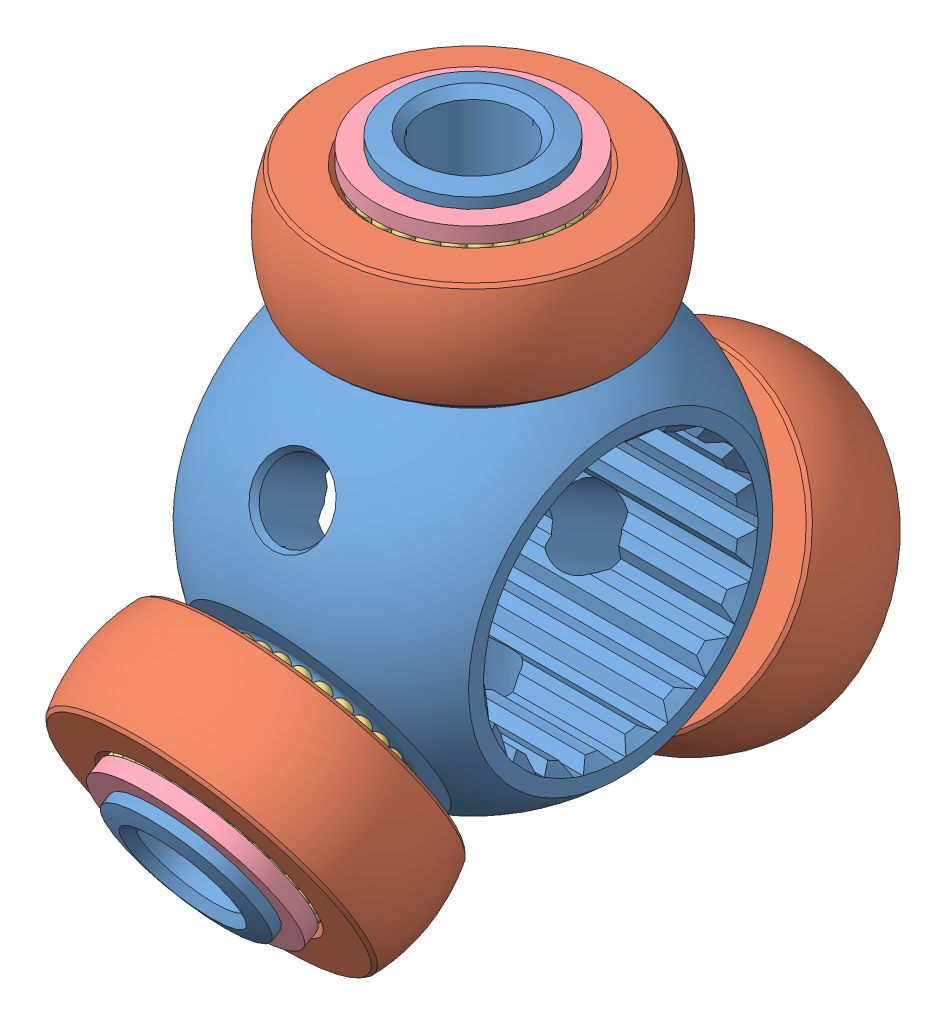
SolidWorks assembly RCV D4672-TA, configuration Default. Lengths in mm.
Overall size (25.48 60.73 70.13).
94 component instances, 4 part files, 0 mates.
Components (placement in the parent):
- FSAE Tripod V2-1: FSAE Tripod V2 [Default] at (-43.6945 4.946 19.6967) size (24 46.2 52.92)
- FSAE roller_2451-1: FSAE roller_2451 [Default] at (-43.6945 -7.4365 -1.7504) x (0 0.5 0.866025) z (-1 0 0) size (25.48 25.48 25.48)
- FSAE roller_2451-2: FSAE roller_2451 [Default] at (-43.6945 -7.4365 41.1438) x (0 0.5 -0.866025) z (1 0 0) size (25.48 25.48 25.48)
- FSAE roller_2451-3: FSAE roller_2451 [Default] at (-43.6945 29.711 19.6967) x (0 -1 0) z (-1 0 0) size (25.48 25.48 25.48)
- needle-1: needle [Default] at (-42.3538 -7.5483 -1.6859) x (1 0 0) z (0 0.5 0.866025) size (1.51 1.51 10.16)
- needle-2: needle [Default] at (-42.3574 -7.2961 -1.8314) x (0.976635 0.186114 -0.107453) z (0 0.5 0.866025) size (1.51 1.51 10.16)
- needle-3: needle [Default] at (-42.4235 -7.0506 -1.9732) x (0.907631 0.363531 -0.209884) z (0 0.5 0.866025) size (1.51 1.51 10.16)
- needle-4: needle [Default] at (-42.5489 -6.823 -2.1046) x (0.796213 0.523959 -0.302508) z (0 0.5 0.866025) size (1.51 1.51 10.16)
- needle-5: needle [Default] at (-42.7279 -6.6242 -2.2194) x (0.647588 0.659903 -0.380995) z (0 0.5 0.866025) size (1.51 1.51 10.16)
- needle-6: needle [Default] at (-42.9521 -6.4632 -2.3123) x (0.468701 0.76501 -0.441678) z (0 0.5 0.866025) size (1.51 1.51 10.16)
- needle-7: needle [Default] at (-43.2109 -6.3478 -2.3789) x (0.267911 0.834367 -0.481722) z (0 0.5 0.866025) size (1.51 1.51 10.16)
- needle-8: needle [Default] at (-43.4924 -6.2833 -2.4162) x (0.054602 0.864733 -0.499254) z (0 0.5 0.866025) size (1.51 1.51 10.16)
- needle-9: needle [Default] at (-43.7833 -6.2726 -2.4224) x (-0.161259 0.854691 -0.493456) z (0 0.5 0.866025) size (1.51 1.51 10.16)
- needle-10: needle [Default] at (-44.07 -6.3163 -2.3971) x (-0.369585 0.804708 -0.464599) z (0 0.5 0.866025) size (1.51 1.51 10.16)
- needle-11: needle [Default] at (-44.3392 -6.4124 -2.3417) x (-0.560639 0.717121 -0.41403) z (0 0.5 0.866025) size (1.51 1.51 10.16)
- needle-12: needle [Default] at (-44.5783 -6.5563 -2.2586) x (-0.725495 0.596023 -0.344114) z (0 0.5 0.866025) size (1.51 1.51 10.16)
- needle-13: needle [Default] at (-44.7761 -6.7413 -2.1517) x (-0.856447 0.447072 -0.258117) z (0 0.5 0.866025) size (1.51 1.51 10.16)
- needle-14: needle [Default] at (-44.9233 -6.9589 -2.0261) x (-0.947378 0.277229 -0.160058) z (0 0.5 0.866025) size (1.51 1.51 10.16)
- needle-15: needle [Default] at (-45.0131 -7.1987 -1.8877) x (-0.994037 0.094432 -0.05452) z (0 0.5 0.866025) size (1.51 1.51 10.16)
- needle-16: needle [Default] at (-45.0413 -7.4497 -1.7428) x (-0.994245 -0.092779 0.053566) z (0 0.5 0.866025) size (1.51 1.51 10.16)
- needle-17: needle [Default] at (-45.0065 -7.7 -1.5982) x (-0.947991 -0.275654 0.159149) z (0 0.5 0.866025) size (1.51 1.51 10.16)
- needle-18: needle [Default] at (-44.9105 -7.9381 -1.4608) x (-0.857437 -0.445647 0.257295) z (0 0.5 0.866025) size (1.51 1.51 10.16)
- needle-19: needle [Default] at (-44.7576 -8.1527 -1.3369) x (-0.726814 -0.594816 0.343417) z (0 0.5 0.866025) size (1.51 1.51 10.16)
- needle-20: needle [Default] at (-44.555 -8.3338 -1.2323) x (-0.562228 -0.716188 0.413491) z (0 0.5 0.866025) size (1.51 1.51 10.16)
- needle-21: needle [Default] at (-44.3122 -8.473 -1.152) x (-0.371368 -0.804092 0.464243) z (0 0.5 0.866025) size (1.51 1.51 10.16)
- needle-22: needle [Default] at (-44.0406 -8.5637 -1.0996) x (-0.163154 -0.854421 0.4933) z (0 0.5 0.866025) size (1.51 1.51 10.16)
- needle-23: needle [Default] at (-43.7528 -8.6018 -1.0776) x (0.052685 -0.864823 0.499306) z (0 0.5 0.866025) size (1.51 1.51 10.16)
- needle-24: needle [Default] at (-43.4622 -8.5854 -1.0871) x (0.266061 -0.834811 0.481978) z (0 0.5 0.866025) size (1.51 1.51 10.16)
- needle-25: needle [Default] at (-43.1825 -8.5153 -1.1275) x (0.467004 -0.765787 0.442128) z (0 0.5 0.866025) size (1.51 1.51 10.16)
- needle-26: needle [Default] at (-42.9268 -8.3949 -1.1971) x (0.646124 -0.660979 0.381616) z (0 0.5 0.866025) size (1.51 1.51 10.16)
- needle-27: needle [Default] at (-42.7069 -8.2296 -1.2925) x (0.79505 -0.525282 0.303272) z (0 0.5 0.866025) size (1.51 1.51 10.16)
- needle-28: needle [Default] at (-42.5332 -8.0272 -1.4093) x (0.906823 -0.365039 0.210755) z (0 0.5 0.866025) size (1.51 1.51 10.16)
- needle-29: needle [Default] at (-42.4137 -7.7973 -1.5421) x (0.97622 -0.187737 0.10839) z (0 0.5 0.866025) size (1.51 1.51 10.16)
- needle-30: needle [Default] at (-42.3538 29.711 19.5676) x (1 0 0) z (0 -1 0) size (1.51 1.51 10.16)
- needle-31: needle [Default] at (-42.3538 -7.3247 41.2084) x (1 0 0) z (0 0.5 -0.866025) size (1.51 1.51 10.16)
- needle-32: needle [Default] at (-42.4137 29.711 19.2801) x (0.97622 0 -0.21678) z (0 -1 0) size (1.51 1.51 10.16)
- needle-33: needle [Default] at (-42.4137 -7.0756 41.3522) x (0.97622 0.187737 0.10839) z (0 0.5 -0.866025) size (1.51 1.51 10.16)
- needle-34: needle [Default] at (-42.5332 29.711 19.0146) x (0.906823 0 -0.421511) z (0 -1 0) size (1.51 1.51 10.16)
- needle-35: needle [Default] at (-42.5332 -6.8457 41.4849) x (0.906823 0.365039 0.210755) z (0 0.5 -0.866025) size (1.51 1.51 10.16)
- needle-36: needle [Default] at (-42.7069 29.711 18.7809) x (0.79505 0 -0.606544) z (0 -1 0) size (1.51 1.51 10.16)
- needle-37: needle [Default] at (-42.7069 -6.6434 41.6017) x (0.79505 0.525282 0.303272) z (0 0.5 -0.866025) size (1.51 1.51 10.16)
- needle-38: needle [Default] at (-42.9268 29.711 18.5901) x (0.646124 0 -0.763232) z (0 -1 0) size (1.51 1.51 10.16)
- needle-39: needle [Default] at (-42.9268 -6.4781 41.6972) x (0.646124 0.660979 0.381616) z (0 0.5 -0.866025) size (1.51 1.51 10.16)
- needle-40: needle [Default] at (-43.1825 29.711 18.4509) x (0.467004 0 -0.884255) z (0 -1 0) size (1.51 1.51 10.16)
- needle-41: needle [Default] at (-43.1825 -6.3576 41.7667) x (0.467004 0.765787 0.442128) z (0 0.5 -0.866025) size (1.51 1.51 10.16)
- needle-42: needle [Default] at (-43.4622 29.711 18.37) x (0.266061 0 -0.963956) z (0 -1 0) size (1.51 1.51 10.16)
- needle-43: needle [Default] at (-43.4622 -6.2875 41.8072) x (0.266061 0.834811 0.481978) z (0 0.5 -0.866025) size (1.51 1.51 10.16)
- needle-44: needle [Default] at (-43.7528 29.711 18.3511) x (0.052685 0 -0.998611) z (0 -1 0) size (1.51 1.51 10.16)
- needle-45: needle [Default] at (-43.7528 -6.2711 41.8166) x (0.052685 0.864823 0.499306) z (0 0.5 -0.866025) size (1.51 1.51 10.16)
- needle-46: needle [Default] at (-44.0406 29.711 18.3951) x (-0.163154 0 -0.986601) z (0 -1 0) size (1.51 1.51 10.16)
- needle-47: needle [Default] at (-44.0406 -6.3092 41.7947) x (-0.163154 0.854421 0.4933) z (0 0.5 -0.866025) size (1.51 1.51 10.16)
- needle-48: needle [Default] at (-44.3122 29.711 18.4999) x (-0.371368 0 -0.928486) z (0 -1 0) size (1.51 1.51 10.16)
- needle-49: needle [Default] at (-44.3122 -6.4 41.7423) x (-0.371368 0.804092 0.464243) z (0 0.5 -0.866025) size (1.51 1.51 10.16)
- needle-50: needle [Default] at (-44.555 29.711 18.6606) x (-0.562228 0 -0.826982) z (0 -1 0) size (1.51 1.51 10.16)
- needle-51: needle [Default] at (-44.555 -6.5392 41.6619) x (-0.562228 0.716188 0.413491) z (0 0.5 -0.866025) size (1.51 1.51 10.16)
- needle-52: needle [Default] at (-44.7576 29.711 18.8697) x (-0.726814 0 -0.686834) z (0 -1 0) size (1.51 1.51 10.16)
- needle-53: needle [Default] at (-44.7576 -6.7203 41.5573) x (-0.726814 0.594816 0.343417) z (0 0.5 -0.866025) size (1.51 1.51 10.16)
- needle-54: needle [Default] at (-44.9105 29.711 19.1175) x (-0.857437 0 -0.514589) z (0 -1 0) size (1.51 1.51 10.16)
- needle-55: needle [Default] at (-44.9105 -6.9349 41.4334) x (-0.857437 0.445647 0.257295) z (0 0.5 -0.866025) size (1.51 1.51 10.16)
- needle-56: needle [Default] at (-45.0065 29.711 19.3924) x (-0.947991 0 -0.318298) z (0 -1 0) size (1.51 1.51 10.16)
- needle-57: needle [Default] at (-45.0065 -7.1729 41.296) x (-0.947991 0.275654 0.159149) z (0 0.5 -0.866025) size (1.51 1.51 10.16)
- needle-58: needle [Default] at (-45.0413 29.711 19.6814) x (-0.994245 0 -0.107132) z (0 -1 0) size (1.51 1.51 10.16)
- needle-59: needle [Default] at (-45.0413 -7.4232 41.1515) x (-0.994245 0.092779 0.053566) z (0 0.5 -0.866025) size (1.51 1.51 10.16)
- needle-60: needle [Default] at (-45.0131 29.711 19.9712) x (-0.994037 0 0.10904) z (0 -1 0) size (1.51 1.51 10.16)
- needle-61: needle [Default] at (-45.0131 -7.6742 41.0066) x (-0.994037 -0.094432 -0.05452) z (0 0.5 -0.866025) size (1.51 1.51 10.16)
- needle-62: needle [Default] at (-44.9233 29.711 20.2482) x (-0.947378 0 0.320117) z (0 -1 0) size (1.51 1.51 10.16)
- needle-63: needle [Default] at (-44.9233 -7.914 40.8681) x (-0.947378 -0.277229 -0.160058) z (0 0.5 -0.866025) size (1.51 1.51 10.16)
- needle-64: needle [Default] at (-44.7761 29.711 20.4994) x (-0.856447 0 0.516234) z (0 -1 0) size (1.51 1.51 10.16)
- needle-65: needle [Default] at (-44.7761 -8.1316 40.7425) x (-0.856447 -0.447072 -0.258117) z (0 0.5 -0.866025) size (1.51 1.51 10.16)
- needle-66: needle [Default] at (-44.5783 29.711 20.7131) x (-0.725495 0 0.688228) z (0 -1 0) size (1.51 1.51 10.16)
- needle-67: needle [Default] at (-44.5783 -8.3166 40.6357) x (-0.725495 -0.596023 -0.344114) z (0 0.5 -0.866025) size (1.51 1.51 10.16)
- needle-68: needle [Default] at (-44.3392 29.711 20.8792) x (-0.560639 0 0.82806) z (0 -1 0) size (1.51 1.51 10.16)
- needle-69: needle [Default] at (-44.3392 -8.4606 40.5526) x (-0.560639 -0.717121 -0.41403) z (0 0.5 -0.866025) size (1.51 1.51 10.16)
- needle-70: needle [Default] at (-44.07 29.711 20.9902) x (-0.369585 0 0.929197) z (0 -1 0) size (1.51 1.51 10.16)
- needle-71: needle [Default] at (-44.07 -8.5566 40.4971) x (-0.369585 -0.804708 -0.464599) z (0 0.5 -0.866025) size (1.51 1.51 10.16)
- needle-72: needle [Default] at (-43.7833 29.711 21.0407) x (-0.161259 0 0.986912) z (0 -1 0) size (1.51 1.51 10.16)
- needle-73: needle [Default] at (-43.7833 -8.6003 40.4719) x (-0.161259 -0.854691 -0.493456) z (0 0.5 -0.866025) size (1.51 1.51 10.16)
- needle-74: needle [Default] at (-43.4924 29.711 21.0283) x (0.054602 0 0.998508) z (0 -1 0) size (1.51 1.51 10.16)
- needle-75: needle [Default] at (-43.4924 -8.5897 40.478) x (0.054602 -0.864733 -0.499254) z (0 0.5 -0.866025) size (1.51 1.51 10.16)
- needle-76: needle [Default] at (-43.2109 29.711 20.9538) x (0.267911 0 0.963444) z (0 -1 0) size (1.51 1.51 10.16)
- needle-77: needle [Default] at (-43.2109 -8.5251 40.5153) x (0.267911 -0.834367 -0.481722) z (0 0.5 -0.866025) size (1.51 1.51 10.16)
- needle-78: needle [Default] at (-42.9521 29.711 20.8205) x (0.468701 0 0.883357) z (0 -1 0) size (1.51 1.51 10.16)
- needle-79: needle [Default] at (-42.9521 -8.4097 40.582) x (0.468701 -0.76501 -0.441678) z (0 0.5 -0.866025) size (1.51 1.51 10.16)
- needle-80: needle [Default] at (-42.7279 29.711 20.6347) x (0.647588 0 0.761991) z (0 -1 0) size (1.51 1.51 10.16)
- needle-81: needle [Default] at (-42.7279 -8.2488 40.6749) x (0.647588 -0.659903 -0.380995) z (0 0.5 -0.866025) size (1.51 1.51 10.16)
- needle-82: needle [Default] at (-42.5489 29.711 20.4051) x (0.796213 0 0.605016) z (0 -1 0) size (1.51 1.51 10.16)
- needle-83: needle [Default] at (-42.5489 -8.0499 40.7897) x (0.796213 -0.523959 -0.302508) z (0 0.5 -0.866025) size (1.51 1.51 10.16)
- needle-84: needle [Default] at (-42.4235 29.711 20.1423) x (0.907631 0 0.419769) z (0 -1 0) size (1.51 1.51 10.16)
- needle-85: needle [Default] at (-42.4235 -7.8224 40.921) x (0.907631 -0.363531 -0.209884) z (0 0.5 -0.866025) size (1.51 1.51 10.16)
- needle-86: needle [Default] at (-42.3574 29.711 19.8588) x (0.976635 0 0.214906) z (0 -1 0) size (1.51 1.51 10.16)
- needle-87: needle [Default] at (-42.3574 -7.5768 41.0628) x (0.976635 -0.186114 -0.107453) z (0 0.5 -0.866025) size (1.51 1.51 10.16)
- Tripod Retainer-1: Tripod Retainer [Default] at (-43.6945 -8.0715 -2.8502) x (0.973299 0.198788 -0.11477) z (0 0.5 0.866025) size (15.88 15.88 1.27)
- Tripod Retainer-2: Tripod Retainer [Default] at (-43.6945 -8.0715 42.2437) x (0.973299 -0.198788 -0.11477) z (0 0.5 -0.866025) size (15.88 15.88 1.27)
- Tripod Retainer-3: Tripod Retainer [Default] at (-43.6945 30.981 19.6967) x (0.973299 0 0.229541) z (0 -1 0) size (15.88 15.88 1.27)
